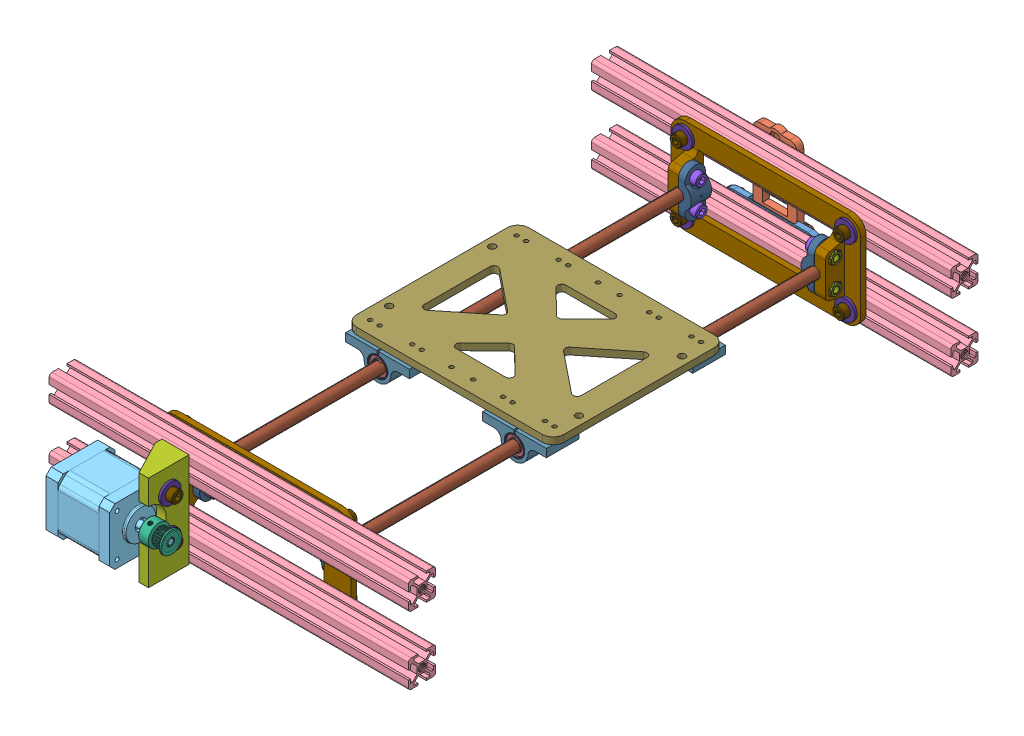
SolidWorks assembly Assembly_Y-Axis, configuration Default. Lengths in mm.
Overall size (265 71.5 493.71).
75 component instances, 20 part files, 169 mates.
Components (placement in the parent):
- Y Idler Mount-1: Y Idler Mount [Default] at (-290.2209 60.0349 127.2239) size (73.51 20 15)
- Y Idler Tensioner-2: Y Idler Tensioner [Default] at (-237.7209 60.0349 124.7239) x (-1 0 0) z (0 -1 0) size (32.5 17.63 71.5)
- instrument ball bearing_ai-1: instrument ball bearing_ai [AFBMA 12.2 - 0.3750 - 0.8750 - 0.2812 - 10,SI,NC,10] at (-250.0422 94.9749 116.2239) size (7.14 22.23 22.23)
- instrument ball bearing_ai-2: instrument ball bearing_ai [AFBMA 12.2 - 0.3750 - 0.8750 - 0.2812 - 10,SI,NC,10] at (-257.8997 94.9749 116.2239) size (7.14 22.23 22.23)
- 8020 26.5cm-1: 8020 26.5cm [Default] at (-366.7209 70.0349 137.2239) x (0 0 -1) z (1 0 0) size (20 20 265)
- 8020 26.5cm-2: 8020 26.5cm [Default] at (-366.7209 120.0349 137.2239) x (0 0 -1) z (1 0 0) size (20 20 265)
- 8020 26.5cm-3: 8020 26.5cm [Default] at (-101.7209 70.0349 537.2239) x (0 0 1) z (-1 0 0) size (20 20 265)
- 8020 26.5cm-4: 8020 26.5cm [Default] at (-101.7209 120.0349 537.2239) x (0 0 1) z (-1 0 0) size (20 20 265)
- Motor - NEMA17-1: Motor - NEMA17 [Default] at (-270.4709 98.1349 577.8256) x (0 -1 0) z (1 0 0) size (42 42 71)
- Motor Rotor Belt holder-1: Motor Rotor Belt holder [Default] at (-253.8985 99.0896 575.515) x (-1 0 0) z (0 -0.924225 -0.381849) size (16.47 16 16)
- YMotorMount-1: YMotorMount [Default] at (-263.4709 60.0349 547.2239) x (0 1 0) z (1 0 0) size (70 30 20)
- socket head cap screw_am-4: socket head cap screw_am [B18.3.1M - 5 x 0.8 x 10 Hex SHCS -- 10CHX] at (-276.4709 120.0349 557.2239) x (0 0 -1) z (1 0 0) size (15 8.5 8.5)
- socket head cap screw_am-5: socket head cap screw_am [B18.3.1M - 5 x 0.8 x 10 Hex SHCS -- 10CHX] at (-276.4709 70.0349 557.2239) x (0 0 -1) z (1 0 0) size (15 8.5 8.5)
- hollow_bracket-2: hollow_bracket [Default] at (-304.2209 60.0349 147.2239) size (140 70 18)
- hollow_bracket-3: hollow_bracket [Default] at (-164.2209 60.0349 527.2239) x (-1 0 0) z (0 0 -1) size (140 70 18)
- 7.5mm speed bump-1: 7.5mm speed bump [Default] at (-184.2209 95.1599 516.2239) x (0 1 0) z (0 0 1) size (35 10 15)
- 7.5mm speed bump-2: 7.5mm speed bump [Default] at (-284.2209 95.1599 516.2239) x (0 -1 0) z (0 0 1) size (35 10 15)
- 7.5mm speed bump-3: 7.5mm speed bump [Default] at (-284.2209 95.1599 158.2239) x (0 -1 0) z (0 0 1) size (35 10 15)
- 7.5mm speed bump-4: 7.5mm speed bump [Default] at (-184.2209 95.1599 158.2239) x (0 1 0) z (0 0 1) size (35 10 15)
- 38cm Aluminum rod-1: 38cm Aluminum rod [Default] at (-184.2209 95.0349 147.2239) size (7.94 7.94 380)
- 38cm Aluminum rod-2: 38cm Aluminum rod [Default] at (-284.2209 95.0349 147.2239) size (7.94 7.94 380)
- X Sub Plate-1: X Sub Plate [Default] at (-158.2023 110.0577 257.0427) x (-1 0 0) z (0 0 1) size (153 5 127)
- LM8UU-1: LM8UU [Default] at (-285.1836 95.0349 374.5427) x (0 0 -1) z (0.555945 0.831219 0) size (24 15 15)
- LM8UU_Bearing_Holder_(full_Circle_Speedbump)-1: LM8UU_Bearing_Holder_(full_Circle_Speedbump) [Default] at (-308.7023 105.0577 386.5427) x (1 0 0) z (0 1 0) size (47 24 20.05)
- LM8UU-2: LM8UU [Default] at (-285.1836 95.0349 266.5427) x (0 0 -1) z (0.555945 0.831219 0) size (24 15 15)
- LM8UU-3: LM8UU [Default] at (-184.2209 95.0349 266.5427) x (0 0 -1) z (0.555945 0.831219 0) size (24 15 15)
- LM8UU_Bearing_Holder_(full_Circle_Speedbump)-2: LM8UU_Bearing_Holder_(full_Circle_Speedbump) [Default] at (-207.7395 105.0577 278.5427) x (1 0 0) z (0 1 0) size (47 24 20.05)
- LM8UU_Bearing_Holder_(full_Circle_Speedbump)-3: LM8UU_Bearing_Holder_(full_Circle_Speedbump) [Default] at (-308.7023 105.0577 278.5427) x (1 0 0) z (0 1 0) size (47 24 20.05)
- LM8UU-4: LM8UU [Default] at (-184.2209 95.0349 374.5427) x (0 0 -1) z (0.555945 0.831219 0) size (24 15 15)
- LM8UU_Bearing_Holder_(full_Circle_Speedbump)-4: LM8UU_Bearing_Holder_(full_Circle_Speedbump) [Default] at (-207.7395 105.0577 386.5427) x (1 0 0) z (0 1 0) size (47 24 20.05)
- socket head cap screw_am-24: socket head cap screw_am [B18.3.1M - 5 x 0.8 x 10 Hex SHCS -- 10CHX] at (-229.2209 66.0349 118.2239) x (-1 0 0) z (0 0.924225 0.381849) size (15 8.5 8.5)
- socket set screw oval point_am-1: socket set screw oval point_am [B18.3.6M - M3 x 0.5 x 5 Hex Socket Oval Pt. SS --C] at (-258.5439 105.616 580.9059) x (-0.021896 -0.941534 -0.336206) z (-0.516982 0.298498 -0.802264) size (5 3 3)
- socket head cap screw_am-26: socket head cap screw_am [B18.3.1M - 5 x 0.8 x 10 Hex SHCS -- 10CHX] at (-274.2209 105.1599 516.2239) x (-1 0 0) z (0 0.924225 0.381849) size (15 8.5 8.5)
- socket head cap screw_am-27: socket head cap screw_am [B18.3.1M - 5 x 0.8 x 10 Hex SHCS -- 10CHX] at (-194.2209 105.1599 516.2239) size (15 8.5 8.5)
- socket head cap screw_am-28: socket head cap screw_am [B18.3.1M - 5 x 0.8 x 10 Hex SHCS -- 10CHX] at (-194.2209 85.1599 516.2239) size (15 8.5 8.5)
- socket head cap screw_am-29: socket head cap screw_am [B18.3.1M - 5 x 0.8 x 10 Hex SHCS -- 10CHX] at (-274.2209 85.1599 516.2239) x (-1 0 0) z (0 0.924225 0.381849) size (15 8.5 8.5)
- socket head cap screw_am-30: socket head cap screw_am [B18.3.1M - 5 x 0.8 x 10 Hex SHCS -- 10CHX] at (-274.2209 85.1599 158.2239) x (-1 0 0) z (0 0.924225 0.381849) size (15 8.5 8.5)
- socket head cap screw_am-31: socket head cap screw_am [B18.3.1M - 5 x 0.8 x 10 Hex SHCS -- 10CHX] at (-274.2209 105.1599 158.2239) x (-1 0 0) z (0 0.924225 0.381849) size (15 8.5 8.5)
- socket head cap screw_am-32: socket head cap screw_am [B18.3.1M - 5 x 0.8 x 10 Hex SHCS -- 10CHX] at (-194.2209 105.1599 158.2239) size (15 8.5 8.5)
- socket head cap screw_am-33: socket head cap screw_am [B18.3.1M - 5 x 0.8 x 10 Hex SHCS -- 10CHX] at (-194.2209 85.1599 158.2239) size (15 8.5 8.5)
- socket head cap screw_am-34: socket head cap screw_am [B18.3.1M - 5 x 0.8 x 10 Hex SHCS -- 10CHX] at (-280.2209 66.0349 118.2239) size (15 8.5 8.5)
- AM-M5-C-2: AM-M5-C [AM-M5-C] at (-174.9209 84.9099 516.2239) x (0 0 -1) z (1 0 0) size (8 9.81 5.3)
- AM-M5-C-3: AM-M5-C [AM-M5-C] at (-174.9209 105.1599 516.2239) x (0 0 -1) z (1 0 0) size (8 9.81 5.3)
- AM-M5-C-4: AM-M5-C [AM-M5-C] at (-174.9209 105.1599 158.2239) x (0 0 -1) z (1 0 0) size (8 9.81 5.3)
- AM-M5-C-5: AM-M5-C [AM-M5-C] at (-174.9209 84.9099 158.2239) x (0 0 -1) z (1 0 0) size (8 9.81 5.3)
- AM-M5-C-6: AM-M5-C [AM-M5-C] at (-293.5209 105.1599 158.2239) x (0 0 1) z (-1 0 0) size (8 9.81 5.3)
- AM-M5-C-7: AM-M5-C [AM-M5-C] at (-293.5209 84.9099 158.2239) x (0 0 1) z (-1 0 0) size (8 9.81 5.3)
- AM-M5-C-8: AM-M5-C [AM-M5-C] at (-293.5209 105.1599 516.2239) x (0 0 1) z (-1 0 0) size (8 9.81 5.3)
- AM-M5-C-9: AM-M5-C [AM-M5-C] at (-293.5209 84.9099 516.2239) x (0 0 1) z (-1 0 0) size (8 9.81 5.3)
- B18.22M - Plain washer, 5 mm, regular-1: B18.22M - Plain washer, 5 mm, regular [B18.22M - Plain washer, 5 mm, regular] at (-263.4709 113.6349 562.3256) x (-1 0 0) z (0 0.924225 0.381849) size (1.75 15 15)
- B18.22M - Plain washer, 5 mm, regular-2: B18.22M - Plain washer, 5 mm, regular [B18.22M - Plain washer, 5 mm, regular] at (-263.4709 84.0349 562.3256) x (-1 0 0) z (0 0.924225 0.381849) size (1.75 15 15)
- B18.22M - Plain washer, 5 mm, regular-3: B18.22M - Plain washer, 5 mm, regular [B18.22M - Plain washer, 5 mm, regular] at (-174.2209 120.0349 523.2239) x (0 0 1) z (-1 0 0) size (1.75 15 15)
- B18.22M - Plain washer, 5 mm, regular-4: B18.22M - Plain washer, 5 mm, regular [B18.22M - Plain washer, 5 mm, regular] at (-294.2209 120.0349 523.2239) x (0 0 1) z (-1 0 0) size (1.75 15 15)
- B18.22M - Plain washer, 5 mm, regular-5: B18.22M - Plain washer, 5 mm, regular [B18.22M - Plain washer, 5 mm, regular] at (-294.2209 70.0349 523.2239) x (0 0 1) z (-1 0 0) size (1.75 15 15)
- B18.22M - Plain washer, 5 mm, regular-6: B18.22M - Plain washer, 5 mm, regular [B18.22M - Plain washer, 5 mm, regular] at (-174.2209 70.0349 523.2239) x (0 0 1) z (-1 0 0) size (1.75 15 15)
- B18.22M - Plain washer, 5 mm, regular-7: B18.22M - Plain washer, 5 mm, regular [B18.22M - Plain washer, 5 mm, regular] at (-285.4749 70.0349 123.2239) x (0 0 1) z (-1 0 0) size (1.75 15 15)
- B18.22M - Plain washer, 5 mm, regular-8: B18.22M - Plain washer, 5 mm, regular [B18.22M - Plain washer, 5 mm, regular] at (-223.9669 70.0349 123.2239) x (0 0 1) z (-1 0 0) size (1.75 15 15)
- B18.22M - Plain washer, 5 mm, regular-9: B18.22M - Plain washer, 5 mm, regular [B18.22M - Plain washer, 5 mm, regular] at (-294.2209 120.0349 151.2239) x (0 0 -1) z (1 0 0) size (1.75 15 15)
- B18.22M - Plain washer, 5 mm, regular-10: B18.22M - Plain washer, 5 mm, regular [B18.22M - Plain washer, 5 mm, regular] at (-174.2209 120.0349 151.2239) x (0 0 -1) z (1 0 0) size (1.75 15 15)
- B18.22M - Plain washer, 5 mm, regular-11: B18.22M - Plain washer, 5 mm, regular [B18.22M - Plain washer, 5 mm, regular] at (-294.2209 70.0349 151.2239) x (0 0 -1) z (1 0 0) size (1.75 15 15)
- B18.22M - Plain washer, 5 mm, regular-12: B18.22M - Plain washer, 5 mm, regular [B18.22M - Plain washer, 5 mm, regular] at (-174.2209 70.0349 151.2239) x (0 0 -1) z (1 0 0) size (1.75 15 15)
- B18.3.1M - 5 x 0.8 x 10 Hex SHCS -- 10CHX-7: B18.3.1M - 5 x 0.8 x 10 Hex SHCS -- 10CHX [B18.3.1M - 5 x 0.8 x 10 Hex SHCS -- 10CHX] at (-294.2209 120.0349 157.9739) x (0 0 -1) z (1 0 0) size (15 8.5 8.5)
- B18.3.1M - 5 x 0.8 x 10 Hex SHCS -- 10CHX-8: B18.3.1M - 5 x 0.8 x 10 Hex SHCS -- 10CHX [B18.3.1M - 5 x 0.8 x 10 Hex SHCS -- 10CHX] at (-294.2209 70.0349 157.9739) x (0 0 -1) z (1 0 0) size (15 8.5 8.5)
- B18.3.1M - 5 x 0.8 x 10 Hex SHCS -- 10CHX-9: B18.3.1M - 5 x 0.8 x 10 Hex SHCS -- 10CHX [B18.3.1M - 5 x 0.8 x 10 Hex SHCS -- 10CHX] at (-174.2209 120.0349 157.9739) x (0 0 -1) z (1 0 0) size (15 8.5 8.5)
- B18.3.1M - 5 x 0.8 x 10 Hex SHCS -- 10CHX-10: B18.3.1M - 5 x 0.8 x 10 Hex SHCS -- 10CHX [B18.3.1M - 5 x 0.8 x 10 Hex SHCS -- 10CHX] at (-174.2209 70.0349 157.9739) x (0 0 -1) z (1 0 0) size (15 8.5 8.5)
- B18.3.1M - 5 x 0.8 x 10 Hex SHCS -- 10CHX-11: B18.3.1M - 5 x 0.8 x 10 Hex SHCS -- 10CHX [B18.3.1M - 5 x 0.8 x 10 Hex SHCS -- 10CHX] at (-223.9669 70.0349 116.4739) x (0 0 1) z (-1 0 0) size (15 8.5 8.5)
- B18.3.1M - 5 x 0.8 x 10 Hex SHCS -- 10CHX-12: B18.3.1M - 5 x 0.8 x 10 Hex SHCS -- 10CHX [B18.3.1M - 5 x 0.8 x 10 Hex SHCS -- 10CHX] at (-285.4749 70.0349 116.4739) x (0 0 1) z (-1 0 0) size (15 8.5 8.5)
- B18.3.1M - 5 x 0.8 x 10 Hex SHCS -- 10CHX-13: B18.3.1M - 5 x 0.8 x 10 Hex SHCS -- 10CHX [B18.3.1M - 5 x 0.8 x 10 Hex SHCS -- 10CHX] at (-174.2209 120.0349 516.4739) x (0 0 1) z (-1 0 0) size (15 8.5 8.5)
- B18.3.1M - 5 x 0.8 x 10 Hex SHCS -- 10CHX-14: B18.3.1M - 5 x 0.8 x 10 Hex SHCS -- 10CHX [B18.3.1M - 5 x 0.8 x 10 Hex SHCS -- 10CHX] at (-174.2209 70.0349 516.4739) x (0 0 1) z (-1 0 0) size (15 8.5 8.5)
- B18.3.1M - 5 x 0.8 x 10 Hex SHCS -- 10CHX-15: B18.3.1M - 5 x 0.8 x 10 Hex SHCS -- 10CHX [B18.3.1M - 5 x 0.8 x 10 Hex SHCS -- 10CHX] at (-294.2209 120.0349 516.4739) x (0 0 1) z (-1 0 0) size (15 8.5 8.5)
- B18.3.1M - 5 x 0.8 x 10 Hex SHCS -- 10CHX-16: B18.3.1M - 5 x 0.8 x 10 Hex SHCS -- 10CHX [B18.3.1M - 5 x 0.8 x 10 Hex SHCS -- 10CHX] at (-294.2209 70.0349 516.4739) x (0 0 1) z (-1 0 0) size (15 8.5 8.5)
- B18.3.1M - 5 x 0.8 x 10 Hex SHCS -- 10CHX-17: B18.3.1M - 5 x 0.8 x 10 Hex SHCS -- 10CHX [B18.3.1M - 5 x 0.8 x 10 Hex SHCS -- 10CHX] at (-256.7209 113.6349 562.3256) x (-1 0 0) z (0 0.924225 0.381849) size (15 8.5 8.5)
- B18.3.1M - 5 x 0.8 x 10 Hex SHCS -- 10CHX-18: B18.3.1M - 5 x 0.8 x 10 Hex SHCS -- 10CHX [B18.3.1M - 5 x 0.8 x 10 Hex SHCS -- 10CHX] at (-256.7209 84.0349 562.3256) x (-1 0 0) z (0 0.924225 0.381849) size (15 8.5 8.5)
- B18.2.4.5M - Hex jam nut,  M8 x 1.25 --D-C-2: B18.2.4.5M - Hex jam nut,  M8 x 1.25 --D-C [B18.2.4.5M - Hex jam nut,  M8 x 1.25 --D-C] at (-271.2209 94.9749 116.2239) x (0 0 1) z (-1 0 0) size (13 15.01 4)
- B18.3.1M - 8 x 1.25 x 30 Hex SHCS -- 30CHX-1: B18.3.1M - 8 x 1.25 x 30 Hex SHCS -- 30CHX [B18.3.1M - 8 x 1.25 x 30 Hex SHCS -- 30CHX] at (-232.7209 94.9749 116.2239) x (-1 0 0) z (0 0.924225 0.381849) size (38 13 13)
Mates (geometry in assembly coordinates):
- Coincident3: coincident aligned: plane of Y Idler Mount-1 through (-290.2209 60.0349 123.2239) normal (0 -1 0); plane of Y Idler Tensioner-2 through (-237.7209 60.0349 106.4439) normal (0 -1 0)
- Concentric1: concentric aligned: cylinder of Y Idler Tensioner-2 through (-270.2209 94.9749 116.2239) axis (1 0 0) radius 3.75; circle of instrument ball bearing_ai-1
- Concentric2: concentric aligned: circle of Y Idler Tensioner-2; circle of instrument ball bearing_ai-2
- Distance1: distance = 1.75 mm anti-aligned: plane of instrument ball bearing_ai-2 through (-261.4709 101.6424 116.2239) normal (-1 0 0); plane of Y Idler Tensioner-2 through (-263.2209 80.0349 106.4439) normal (1 0 0)
- Distance2: distance = 1.75 mm anti-aligned: plane of instrument ball bearing_ai-1 through (-246.4709 105.681 116.2239) normal (1 0 0); plane of Y Idler Tensioner-2 through (-244.7209 80.0349 106.4439) normal (-1 0 0)
- Coincident6: coincident anti-aligned: plane of Y Idler Mount-1 through (-290.2209 60.0349 127.2239) normal (0 0 1); plane of 8020 26.5cm-1 through (-101.7209 70.0349 127.2239) normal (0 0 -1)
- Coincident7: coincident aligned: plane of Y Idler Mount-1 through (-290.2209 60.0349 123.2239) normal (0 -1 0); plane of 8020 26.5cm-1 through (-101.7209 60.0349 137.2239) normal (0 -1 0)
- Distance3: distance = 132.5 mm aligned: plane of Y Idler Mount-1 through (-234.2209 66.0349 118.2239) normal (1 0 0); plane of 8020 26.5cm-1 through (-101.7209 70.0349 137.2239) normal (1 0 0)
- Coincident9: coincident aligned: plane of 8020 26.5cm-1 through (-366.7209 70.0349 137.2239) normal (-1 0 0); plane of 8020 26.5cm-2 through (-366.7209 120.0349 137.2239) normal (-1 0 0)
- Coincident21: coincident aligned: plane of 8020 26.5cm-3 through (-366.7209 60.0349 537.2239) normal (0 -1 0); plane of YMotorMount-1 through (-270.4709 60.0349 547.2239) normal (0 -1 0)
- Coincident33: coincident aligned: plane of 8020 26.5cm-4 through (-366.7209 130.0349 537.2239) normal (0 1 0); plane of YMotorMount-1 through (-270.4709 130.0349 547.2239) normal (0 1 0)
- Coincident34: coincident aligned: plane of 8020 26.5cm-3 through (-366.7209 70.0349 537.2239) normal (-1 0 0); plane of 8020 26.5cm-4 through (-366.7209 120.0349 537.2239) normal (-1 0 0)
- Coincident35: coincident aligned: plane of 8020 26.5cm-2 through (-101.7209 130.0349 137.2239) normal (0 1 0); plane of 8020 26.5cm-4 through (-366.7209 130.0349 537.2239) normal (0 1 0)
- Concentric4: concentric aligned: circle of Motor - NEMA17-1; circle of YMotorMount-1
- Parallel4: parallel aligned: plane of Motor - NEMA17-1 through (-278.4709 80.9512 598.8256) normal (0 0 1); plane of YMotorMount-1 through (-270.4709 60.0349 577.2239) normal (0 0 1)
- Coincident37: coincident anti-aligned: plane of Motor - NEMA17-1 through (-270.4709 98.1349 577.8256) normal (1 0 0); plane of YMotorMount-1 through (-270.4709 98.8349 577.2239) normal (-1 0 0)
- Coincident38: coincident aligned: plane of Motor - NEMA17-1 through (-246.4709 98.1349 577.8256) normal (1 0 0); plane of Motor Rotor Belt holder-1 through (-246.4709 99.0896 575.515) normal (1 0 0)
- Coincident39: coincident anti-aligned: cylinder of Motor - NEMA17-1 through (-246.4709 98.1349 577.8256) axis (-1 0 0) radius 2.5; circle of Motor Rotor Belt holder-1
- Coincident40: coincident aligned: plane of instrument ball bearing_ai-1 through (-246.4709 105.681 116.2239) normal (1 0 0); plane of Motor Rotor Belt holder-1 through (-246.4709 99.0896 575.515) normal (1 0 0)
- Concentric81: concentric anti-aligned: cylinder of YMotorMount-1 through (-276.4709 120.0349 552.2239) axis (0 0 -1) radius 3; cylinder of socket head cap screw_am-4 through (-276.4709 120.0349 588.9739) axis (0 0 1) radius 4.25
- Coincident441: coincident anti-aligned: plane of YMotorMount-1 through (-263.4709 60.0349 552.2239) normal (0 0 1); plane of socket head cap screw_am-4 through (-276.4709 124.2849 552.2239) normal (0 0 -1)
- Concentric91: concentric anti-aligned: cylinder of YMotorMount-1 through (-276.4709 70.0349 552.2239) axis (0 0 -1) radius 3; cylinder of socket head cap screw_am-5 through (-276.4709 70.0349 588.9739) axis (0 0 1) radius 4.25
- Coincident451: coincident anti-aligned: plane of YMotorMount-1 through (-263.4709 60.0349 552.2239) normal (0 0 1); plane of socket head cap screw_am-5 through (-276.4709 74.2849 552.2239) normal (0 0 -1)
- Coincident465: coincident aligned: plane of 8020 26.5cm-1 through (-101.7209 70.0349 127.2239) normal (0 0 -1); plane of 8020 26.5cm-2 through (-101.7209 120.0349 127.2239) normal (0 0 -1)
- Coincident466: coincident anti-aligned: plane of 8020 26.5cm-2 through (-101.7209 120.0349 147.2239) normal (0 0 1); plane of hollow_bracket-2 through (-304.2209 60.0349 147.2239) normal (0 0 -1)
- Coincident467: coincident aligned: plane of 8020 26.5cm-2 through (-101.7209 130.0349 137.2239) normal (0 1 0); plane of hollow_bracket-2 through (-304.2209 130.0349 151.2239) normal (0 1 0)
- Distance4: distance = 62.5 mm aligned: plane of 8020 26.5cm-2 through (-366.7209 120.0349 137.2239) normal (-1 0 0); plane of hollow_bracket-2 through (-304.2209 60.0349 151.2239) normal (-1 0 0)
- Coincident469: coincident anti-aligned: plane of 8020 26.5cm-4 through (-366.7209 120.0349 527.2239) normal (0 0 -1); plane of hollow_bracket-3 through (-164.2209 60.0349 527.2239) normal (0 0 1)
- Coincident470: coincident aligned: plane of 8020 26.5cm-4 through (-366.7209 130.0349 537.2239) normal (0 1 0); plane of hollow_bracket-3 through (-164.2209 130.0349 523.2239) normal (0 1 0)
- Coincident471: coincident aligned: plane of hollow_bracket-2 through (-164.2209 60.0349 151.2239) normal (1 0 0); plane of hollow_bracket-3 through (-164.2209 60.0349 523.2239) normal (1 0 0)
- Coincident472: coincident aligned: circle of hollow_bracket-3; circle of 7.5mm speed bump-1
- Parallel6: parallel aligned: plane of hollow_bracket-3 through (-164.2209 60.0349 509.2239) normal (0 0 -1); plane of 7.5mm speed bump-1 through (-193.7209 95.1599 508.7239) normal (0 0 -1)
- Coincident474: coincident aligned: circle of hollow_bracket-3; circle of 7.5mm speed bump-2
- Parallel7: parallel aligned: plane of hollow_bracket-3 through (-164.2209 60.0349 509.2239) normal (0 0 -1); plane of 7.5mm speed bump-2 through (-274.7209 95.1599 508.7239) normal (0 0 -1)
- Coincident477: coincident aligned: circle of hollow_bracket-2; circle of 7.5mm speed bump-4
- Parallel8: parallel aligned: plane of 7.5mm speed bump-4 through (-193.7209 95.1599 165.7239) normal (0 0 1); plane of hollow_bracket-2 through (-304.2209 60.0349 165.2239) normal (0 0 1)
- Coincident482: coincident aligned: circle of hollow_bracket-2; circle of 7.5mm speed bump-3
- Parallel9: parallel aligned: plane of hollow_bracket-2 through (-304.2209 60.0349 165.2239) normal (0 0 1); plane of 7.5mm speed bump-3 through (-274.7209 95.1599 165.7239) normal (0 0 1)
- Concentric102: concentric anti-aligned: circle of hollow_bracket-2; cylinder of 38cm Aluminum rod-1 through (-184.2209 95.0349 527.2239) axis (0 0 -1) radius 3.9688
- Coincident484: coincident aligned: plane of hollow_bracket-2 through (-304.2209 60.0349 147.2239) normal (0 0 -1); plane of 38cm Aluminum rod-1 through (-184.2209 95.0349 147.2239) normal (0 0 -1)
- Concentric103: concentric anti-aligned: cylinder of hollow_bracket-2 through (-284.2209 95.0349 147.2239) axis (0 0 1) radius 4.125; cylinder of 38cm Aluminum rod-2 through (-284.2209 95.0349 527.2239) axis (0 0 -1) radius 3.9688
- Coincident485: coincident aligned: plane of hollow_bracket-2 through (-304.2209 60.0349 147.2239) normal (0 0 -1); plane of 38cm Aluminum rod-2 through (-284.2209 95.0349 147.2239) normal (0 0 -1)
- Concentric104: concentric anti-aligned: cylinder of LM8UU-1 through (-285.1836 95.0349 420.2322) axis (0 0 1) radius 7.5; cylinder of LM8UU_Bearing_Holder_(full_Circle_Speedbump)-1 through (-285.1836 95.0349 386.5427) axis (0 0 -1) radius 7.55
- Coincident486: coincident aligned: circle of LM8UU-1; plane of LM8UU_Bearing_Holder_(full_Circle_Speedbump)-1 through (-270.2023 93.9899 386.5427) normal (0 0 1)
- Concentric105: concentric anti-aligned: cylinder of LM8UU-3 through (-184.2209 95.0349 312.2322) axis (0 0 1) radius 7.5; cylinder of LM8UU_Bearing_Holder_(full_Circle_Speedbump)-2 through (-184.2209 95.0349 278.5427) axis (0 0 -1) radius 7.55
- Concentric106: concentric anti-aligned: cylinder of LM8UU-4 through (-184.2209 95.0349 420.2322) axis (0 0 1) radius 7.5; cylinder of LM8UU_Bearing_Holder_(full_Circle_Speedbump)-4 through (-184.2209 95.0349 386.5427) axis (0 0 -1) radius 7.55
- Concentric107: concentric anti-aligned: cylinder of LM8UU-2 through (-285.1836 95.0349 312.2322) axis (0 0 1) radius 7.5; cylinder of LM8UU_Bearing_Holder_(full_Circle_Speedbump)-3 through (-285.1836 95.0349 278.5427) axis (0 0 -1) radius 7.55
- Coincident487: coincident aligned: plane of LM8UU-4 through (-184.2209 95.0349 362.5427) normal (0 0 -1); plane of LM8UU_Bearing_Holder_(full_Circle_Speedbump)-4 through (-169.2395 93.9899 362.5427) normal (0 0 -1)
- Coincident488: coincident aligned: circle of LM8UU-3; plane of LM8UU_Bearing_Holder_(full_Circle_Speedbump)-2 through (-169.2395 93.9899 278.5427) normal (0 0 1)
- Coincident489: coincident aligned: plane of LM8UU-2 through (-285.1836 95.0349 278.5427) normal (0 0 1); plane of LM8UU_Bearing_Holder_(full_Circle_Speedbump)-3 through (-270.2023 93.9899 278.5427) normal (0 0 1)
- Coincident494: coincident anti-aligned: plane of X Sub Plate-1 through (-158.2023 105.0577 257.0427) normal (0 -1 0); plane of LM8UU_Bearing_Holder_(full_Circle_Speedbump)-2 through (-207.7395 105.0577 278.5427) normal (0 1 0)
- Parallel11: parallel anti-aligned: plane of X Sub Plate-1 through (-158.2023 105.0577 257.0427) normal (0 0 -1); plane of LM8UU_Bearing_Holder_(full_Circle_Speedbump)-2 through (-169.2395 93.9899 278.5427) normal (0 0 1)
- Concentric118: concentric aligned: circle of X Sub Plate-1; circle of LM8UU_Bearing_Holder_(full_Circle_Speedbump)-2
- Coincident496: coincident anti-aligned: plane of X Sub Plate-1 through (-158.2023 105.0577 257.0427) normal (0 -1 0); plane of LM8UU_Bearing_Holder_(full_Circle_Speedbump)-4 through (-207.7395 105.0577 386.5427) normal (0 1 0)
- Concentric119: concentric anti-aligned: circle of X Sub Plate-1; circle of LM8UU_Bearing_Holder_(full_Circle_Speedbump)-4
- Coincident497: coincident anti-aligned: plane of X Sub Plate-1 through (-158.2023 105.0577 257.0427) normal (0 -1 0); plane of LM8UU_Bearing_Holder_(full_Circle_Speedbump)-3 through (-308.7023 105.0577 278.5427) normal (0 1 0)
- Concentric120: concentric anti-aligned: circle of X Sub Plate-1; cylinder of LM8UU_Bearing_Holder_(full_Circle_Speedbump)-3 through (-302.7023 99.0577 266.5427) axis (0 -1 0) radius 2.25
- Coincident498: coincident anti-aligned: plane of X Sub Plate-1 through (-158.2023 105.0577 257.0427) normal (0 -1 0); plane of LM8UU_Bearing_Holder_(full_Circle_Speedbump)-1 through (-308.7023 105.0577 386.5427) normal (0 1 0)
- Concentric122: concentric aligned: circle of X Sub Plate-1; circle of LM8UU_Bearing_Holder_(full_Circle_Speedbump)-1
- Parallel12: parallel aligned: plane of X Sub Plate-1 through (-158.2023 105.0577 384.0427) normal (0 0 1); plane of LM8UU_Bearing_Holder_(full_Circle_Speedbump)-4 through (-169.2395 93.9899 386.5427) normal (0 0 1)
- Parallel13: parallel aligned: plane of X Sub Plate-1 through (-158.2023 105.0577 384.0427) normal (0 0 1); plane of LM8UU_Bearing_Holder_(full_Circle_Speedbump)-1 through (-270.2023 93.9899 386.5427) normal (0 0 1)
- Parallel14: parallel aligned: plane of X Sub Plate-1 through (-158.2023 105.0577 257.0427) normal (0 0 -1); plane of LM8UU_Bearing_Holder_(full_Circle_Speedbump)-2 through (-169.2395 93.9899 254.5427) normal (0 0 -1)
- Parallel15: parallel aligned: plane of X Sub Plate-1 through (-158.2023 105.0577 257.0427) normal (0 0 -1); plane of LM8UU_Bearing_Holder_(full_Circle_Speedbump)-3 through (-270.2023 93.9899 254.5427) normal (0 0 -1)
- Coincident503: coincident aligned: plane of 8020 26.5cm-3 through (-366.7209 60.0349 537.2239) normal (0 -1 0); plane of hollow_bracket-3 through (-164.2209 60.0349 523.2239) normal (0 -1 0)
- Coincident505: coincident aligned: plane of 8020 26.5cm-1 through (-101.7209 70.0349 137.2239) normal (1 0 0); plane of 8020 26.5cm-3 through (-101.7209 70.0349 537.2239) normal (1 0 0)
- Coincident506: coincident aligned: plane of 8020 26.5cm-3 through (-366.7209 70.0349 547.2239) normal (0 0 1); plane of 8020 26.5cm-4 through (-366.7209 120.0349 547.2239) normal (0 0 1)
- Coincident507: coincident aligned: plane of hollow_bracket-3 through (-164.2209 60.0349 527.2239) normal (0 0 1); plane of 38cm Aluminum rod-1 through (-184.2209 95.0349 527.2239) normal (0 0 1)
- Coincident508: coincident aligned: plane of hollow_bracket-3 through (-164.2209 60.0349 527.2239) normal (0 0 1); circle of 38cm Aluminum rod-2
- Coincident509: coincident aligned: plane of hollow_bracket-2 through (-304.2209 60.0349 147.2239) normal (0 0 -1); plane of 38cm Aluminum rod-2 through (-284.2209 95.0349 147.2239) normal (0 0 -1)
- Coincident510: coincident aligned: plane of hollow_bracket-2 through (-304.2209 60.0349 147.2239) normal (0 0 -1); plane of 38cm Aluminum rod-1 through (-184.2209 95.0349 147.2239) normal (0 0 -1)
- Coincident511: coincident aligned: plane of 8020 26.5cm-4 through (-366.7209 130.0349 537.2239) normal (0 1 0); plane of hollow_bracket-3 through (-164.2209 130.0349 523.2239) normal (0 1 0)
- Coincident512: coincident aligned: plane of Y Idler Mount-1 through (-290.2209 60.0349 123.2239) normal (0 -1 0); plane of 8020 26.5cm-1 through (-101.7209 60.0349 137.2239) normal (0 -1 0)
- Coincident513: coincident aligned: plane of 8020 26.5cm-1 through (-101.7209 80.0349 137.2239) normal (0 1 0); plane of 8020 26.5cm-3 through (-366.7209 80.0349 537.2239) normal (0 1 0)
- Coincident514: coincident anti-aligned: plane of 8020 26.5cm-4 through (-366.7209 120.0349 547.2239) normal (0 0 1); plane of YMotorMount-1 through (-270.4709 60.0349 547.2239) normal (0 0 -1)
- Coincident515: coincident aligned: plane of 8020 26.5cm-4 through (-366.7209 130.0349 537.2239) normal (0 1 0); plane of YMotorMount-1 through (-270.4709 130.0349 547.2239) normal (0 1 0)
- Parallel17: parallel anti-aligned: plane of Y Idler Tensioner-2 through (-244.7209 80.0349 106.4439) normal (-1 0 0); plane of Motor Rotor Belt holder-1 through (-246.4709 99.0896 575.515) normal (1 0 0)
- Parallel19: parallel aligned: plane of 8020 26.5cm-4 through (-366.7209 130.0349 537.2239) normal (0 1 0); plane of X Sub Plate-1 through (-158.2023 110.0577 257.0427) normal (0 1 0)
- Concentric130: concentric anti-aligned: cylinder of 38cm Aluminum rod-1 through (-184.2209 95.0349 527.2239) axis (0 0 -1) radius 3.9688; cylinder of LM8UU-4 through (-184.2209 95.0349 420.2322) axis (0 0 1) radius 4
- Concentric1472: concentric anti-aligned: cylinder of Y Idler Mount-1 through (-234.2209 66.0349 118.2239) axis (-1 0 0) radius 3; cylinder of Y Idler Tensioner-2 through (-270.2209 66.0349 118.2239) axis (1 0 0) radius 2.55
- Concentric14731: concentric anti-aligned: cylinder of Y Idler Mount-1 through (-234.2209 66.0349 118.2239) axis (-1 0 0) radius 3; cylinder of socket head cap screw_am-24 through (-197.4709 66.0349 118.2239) axis (1 0 0) radius 4.25
- Coincident53521: coincident anti-aligned: plane of Y Idler Mount-1 through (-234.2209 66.0349 118.2239) normal (1 0 0); plane of socket head cap screw_am-24 through (-234.2209 64.4121 122.1518) normal (-1 0 0)
- Tangent1: tangent: curve of Motor Rotor Belt holder-1; circle of socket set screw oval point_am-1
- Concentric148481: concentric anti-aligned: cylinder of 7.5mm speed bump-2 through (-279.2209 105.1599 516.2239) axis (-1 0 0) radius 2.75; cylinder of socket head cap screw_am-26 through (-242.4709 105.1599 516.2239) axis (1 0 0) radius 4.25
- Coincident536371: coincident anti-aligned: plane of 7.5mm speed bump-2 through (-279.2209 95.1599 516.2239) normal (1 0 0); plane of socket head cap screw_am-26 through (-279.2209 103.5371 520.1518) normal (-1 0 0)
- Concentric148491: concentric anti-aligned: cylinder of 7.5mm speed bump-1 through (-189.2209 105.1599 516.2239) axis (1 0 0) radius 2.75; cylinder of socket head cap screw_am-27 through (-225.9709 105.1599 516.2239) axis (-1 0 0) radius 4.25
- Coincident536381: coincident anti-aligned: plane of 7.5mm speed bump-1 through (-189.2209 95.1599 516.2239) normal (-1 0 0); plane of socket head cap screw_am-27 through (-189.2209 109.4099 516.2239) normal (1 0 0)
- Concentric148501: concentric anti-aligned: cylinder of 7.5mm speed bump-1 through (-189.2209 85.1599 516.2239) axis (1 0 0) radius 2.75; cylinder of socket head cap screw_am-28 through (-225.9709 85.1599 516.2239) axis (-1 0 0) radius 4.25
- Coincident536391: coincident anti-aligned: plane of 7.5mm speed bump-1 through (-189.2209 95.1599 516.2239) normal (-1 0 0); plane of socket head cap screw_am-28 through (-189.2209 89.4099 516.2239) normal (1 0 0)
- Concentric148511: concentric anti-aligned: cylinder of 7.5mm speed bump-2 through (-279.2209 85.1599 516.2239) axis (-1 0 0) radius 2.75; cylinder of socket head cap screw_am-29 through (-242.4709 85.1599 516.2239) axis (1 0 0) radius 4.25
- Coincident536401: coincident anti-aligned: plane of 7.5mm speed bump-2 through (-279.2209 95.1599 516.2239) normal (1 0 0); plane of socket head cap screw_am-29 through (-279.2209 83.5371 520.1518) normal (-1 0 0)
- Concentric148521: concentric anti-aligned: cylinder of 7.5mm speed bump-3 through (-279.2209 85.1599 158.2239) axis (-1 0 0) radius 2.75; cylinder of socket head cap screw_am-30 through (-242.4709 85.1599 158.2239) axis (1 0 0) radius 4.25
- Coincident536411: coincident anti-aligned: plane of 7.5mm speed bump-3 through (-279.2209 95.1599 158.2239) normal (1 0 0); plane of socket head cap screw_am-30 through (-279.2209 83.5371 162.1518) normal (-1 0 0)
- Concentric148531: concentric anti-aligned: cylinder of 7.5mm speed bump-3 through (-274.7209 105.1599 158.2239) axis (-1 0 0) radius 5.5; cylinder of socket head cap screw_am-31 through (-242.4709 105.1599 158.2239) axis (1 0 0) radius 4.25
- Coincident536421: coincident anti-aligned: plane of 7.5mm speed bump-3 through (-279.2209 95.1599 158.2239) normal (1 0 0); plane of socket head cap screw_am-31 through (-279.2209 103.5371 162.1518) normal (-1 0 0)
- Concentric148541: concentric anti-aligned: cylinder of 7.5mm speed bump-4 through (-189.2209 105.1599 158.2239) axis (1 0 0) radius 2.75; cylinder of socket head cap screw_am-32 through (-225.9709 105.1599 158.2239) axis (-1 0 0) radius 4.25
- Coincident536431: coincident anti-aligned: plane of 7.5mm speed bump-4 through (-189.2209 95.1599 158.2239) normal (-1 0 0); plane of socket head cap screw_am-32 through (-189.2209 109.4099 158.2239) normal (1 0 0)
- Concentric148551: concentric anti-aligned: cylinder of 7.5mm speed bump-4 through (-189.2209 85.1599 158.2239) axis (1 0 0) radius 2.75; cylinder of socket head cap screw_am-33 through (-225.9709 85.1599 158.2239) axis (-1 0 0) radius 4.25
- Coincident536441: coincident anti-aligned: plane of 7.5mm speed bump-4 through (-189.2209 95.1599 158.2239) normal (-1 0 0); plane of socket head cap screw_am-33 through (-189.2209 89.4099 158.2239) normal (1 0 0)
- Concentric148561: concentric anti-aligned: cylinder of Y Idler Mount-1 through (-275.2209 66.0349 118.2239) axis (1 0 0) radius 3; cylinder of socket head cap screw_am-34 through (-311.9709 66.0349 118.2239) axis (-1 0 0) radius 4.25
- Coincident536451: coincident anti-aligned: plane of Y Idler Mount-1 through (-275.2209 66.0349 118.2239) normal (-1 0 0); plane of socket head cap screw_am-34 through (-275.2209 70.2849 118.2239) normal (1 0 0)
- Coincident53646: coincident aligned: plane of hollow_bracket-3 through (-164.2209 60.0349 527.2239) normal (0 0 1); plane of 38cm Aluminum rod-1 through (-184.2209 95.0349 527.2239) normal (0 0 1)
- Concentric148571: concentric anti-aligned: cylinder of hollow_bracket-3 through (-180.2209 84.9099 516.2239) axis (-1 0 0) radius 2.75; cylinder of AM-M5-C-2 through (-199.9584 84.9099 516.2239) axis (1 0 0) radius 2.5
- Coincident536471: coincident anti-aligned: plane of hollow_bracket-3 through (-180.2209 60.0349 527.2239) normal (1 0 0); plane of AM-M5-C-2 through (-180.2209 84.9099 524.2239) normal (-1 0 0)
- Concentric148581: concentric anti-aligned: cylinder of hollow_bracket-3 through (-180.2209 105.1599 516.2239) axis (-1 0 0) radius 2.75; cylinder of AM-M5-C-3 through (-199.9584 105.1599 516.2239) axis (1 0 0) radius 2.5
- Coincident536481: coincident anti-aligned: plane of hollow_bracket-3 through (-180.2209 60.0349 527.2239) normal (1 0 0); plane of AM-M5-C-3 through (-180.2209 105.1599 524.2239) normal (-1 0 0)
- Concentric148591: concentric anti-aligned: cylinder of hollow_bracket-2 through (-180.2209 105.1599 158.2239) axis (-1 0 0) radius 2.75; cylinder of AM-M5-C-4 through (-199.9584 105.1599 158.2239) axis (1 0 0) radius 2.5
- Coincident536491: coincident anti-aligned: plane of hollow_bracket-2 through (-180.2209 60.0349 147.2239) normal (1 0 0); plane of AM-M5-C-4 through (-180.2209 105.1599 166.2239) normal (-1 0 0)
- Concentric148601: concentric anti-aligned: cylinder of hollow_bracket-2 through (-180.2209 84.9099 158.2239) axis (-1 0 0) radius 2.75; cylinder of AM-M5-C-5 through (-199.9584 84.9099 158.2239) axis (1 0 0) radius 2.5
- Coincident536501: coincident anti-aligned: plane of hollow_bracket-2 through (-180.2209 60.0349 147.2239) normal (1 0 0); plane of AM-M5-C-5 through (-180.2209 84.9099 166.2239) normal (-1 0 0)
- Concentric148611: concentric anti-aligned: cylinder of hollow_bracket-2 through (-288.2209 105.1599 158.2239) axis (1 0 0) radius 2.75; cylinder of AM-M5-C-6 through (-268.4834 105.1599 158.2239) axis (-1 0 0) radius 2.5
- Coincident536511: coincident anti-aligned: plane of hollow_bracket-2 through (-288.2209 60.0349 147.2239) normal (-1 0 0); plane of AM-M5-C-6 through (-288.2209 105.1599 150.2239) normal (1 0 0)
- Concentric148621: concentric anti-aligned: cylinder of hollow_bracket-2 through (-288.2209 84.9099 158.2239) axis (1 0 0) radius 2.75; cylinder of AM-M5-C-7 through (-268.4834 84.9099 158.2239) axis (-1 0 0) radius 2.5
- Coincident536521: coincident anti-aligned: plane of hollow_bracket-2 through (-288.2209 60.0349 147.2239) normal (-1 0 0); plane of AM-M5-C-7 through (-288.2209 84.9099 150.2239) normal (1 0 0)
- Concentric148631: concentric anti-aligned: cylinder of hollow_bracket-3 through (-288.2209 105.1599 516.2239) axis (1 0 0) radius 2.75; cylinder of AM-M5-C-8 through (-268.4834 105.1599 516.2239) axis (-1 0 0) radius 2.5
- Coincident536531: coincident anti-aligned: plane of hollow_bracket-3 through (-288.2209 60.0349 527.2239) normal (-1 0 0); plane of AM-M5-C-8 through (-288.2209 105.1599 508.2239) normal (1 0 0)
- Concentric148641: concentric anti-aligned: cylinder of hollow_bracket-3 through (-288.2209 84.9099 516.2239) axis (1 0 0) radius 2.75; cylinder of AM-M5-C-9 through (-268.4834 84.9099 516.2239) axis (-1 0 0) radius 2.5
- Coincident536541: coincident anti-aligned: plane of hollow_bracket-3 through (-288.2209 60.0349 527.2239) normal (-1 0 0); plane of AM-M5-C-9 through (-288.2209 84.9099 508.2239) normal (1 0 0)
- Concentric1486421: concentric aligned: cylinder of YMotorMount-1 through (-270.4709 113.6349 562.3256) axis (1 0 0) radius 2.5; cylinder of B18.22M - Plain washer, 5 mm, regular-1 through (-228.5459 113.6349 562.3256) axis (1 0 0) radius 2.89
- Coincident5365421: coincident anti-aligned: plane of YMotorMount-1 through (-263.4709 98.8349 577.2239) normal (1 0 0); plane of B18.22M - Plain washer, 5 mm, regular-1 through (-263.4709 112.5314 564.9966) normal (-1 0 0)
- Concentric1486431: concentric aligned: cylinder of YMotorMount-1 through (-270.4709 84.0349 562.3256) axis (1 0 0) radius 2.5; cylinder of B18.22M - Plain washer, 5 mm, regular-2 through (-228.5459 84.0349 562.3256) axis (1 0 0) radius 2.89
- Coincident5365431: coincident anti-aligned: plane of YMotorMount-1 through (-263.4709 98.8349 577.2239) normal (1 0 0); plane of B18.22M - Plain washer, 5 mm, regular-2 through (-263.4709 82.9314 564.9966) normal (-1 0 0)
- Concentric1486441: concentric anti-aligned: cylinder of hollow_bracket-3 through (-174.2209 120.0349 523.2239) axis (0 0 1) radius 2.75; cylinder of B18.22M - Plain washer, 5 mm, regular-3 through (-174.2209 120.0349 488.2989) axis (0 0 -1) radius 2.89
- Coincident5365441: coincident anti-aligned: plane of hollow_bracket-3 through (-164.2209 60.0349 523.2239) normal (0 0 -1); plane of B18.22M - Plain washer, 5 mm, regular-3 through (-174.2209 122.9249 523.2239) normal (0 0 1)
- Concentric1486451: concentric anti-aligned: cylinder of hollow_bracket-3 through (-294.2209 120.0349 523.2239) axis (0 0 1) radius 2.75; cylinder of B18.22M - Plain washer, 5 mm, regular-4 through (-294.2209 120.0349 488.2989) axis (0 0 -1) radius 2.89
- Coincident5365451: coincident anti-aligned: plane of hollow_bracket-3 through (-164.2209 60.0349 523.2239) normal (0 0 -1); plane of B18.22M - Plain washer, 5 mm, regular-4 through (-294.2209 122.9249 523.2239) normal (0 0 1)
- Concentric1486461: concentric anti-aligned: cylinder of hollow_bracket-3 through (-294.2209 70.0349 523.2239) axis (0 0 1) radius 2.75; cylinder of B18.22M - Plain washer, 5 mm, regular-5 through (-294.2209 70.0349 488.2989) axis (0 0 -1) radius 2.89
- Coincident5365461: coincident anti-aligned: plane of hollow_bracket-3 through (-164.2209 60.0349 523.2239) normal (0 0 -1); plane of B18.22M - Plain washer, 5 mm, regular-5 through (-294.2209 72.9249 523.2239) normal (0 0 1)
- Concentric1486471: concentric anti-aligned: cylinder of hollow_bracket-3 through (-174.2209 70.0349 523.2239) axis (0 0 1) radius 2.75; cylinder of B18.22M - Plain washer, 5 mm, regular-6 through (-174.2209 70.0349 488.2989) axis (0 0 -1) radius 2.89
- Coincident5365471: coincident anti-aligned: plane of hollow_bracket-3 through (-164.2209 60.0349 523.2239) normal (0 0 -1); plane of B18.22M - Plain washer, 5 mm, regular-6 through (-174.2209 72.9249 523.2239) normal (0 0 1)
- Concentric1486481: concentric anti-aligned: cylinder of Y Idler Mount-1 through (-285.4749 70.0349 123.2239) axis (0 0 1) radius 3; cylinder of B18.22M - Plain washer, 5 mm, regular-7 through (-285.4749 70.0349 88.2989) axis (0 0 -1) radius 2.89
- Coincident5365481: coincident anti-aligned: plane of Y Idler Mount-1 through (-290.2209 60.0349 123.2239) normal (0 0 -1); plane of B18.22M - Plain washer, 5 mm, regular-7 through (-285.4749 72.9249 123.2239) normal (0 0 1)
- Concentric1486491: concentric anti-aligned: cylinder of Y Idler Mount-1 through (-223.9669 70.0349 123.2239) axis (0 0 1) radius 3; cylinder of B18.22M - Plain washer, 5 mm, regular-8 through (-223.9669 70.0349 88.2989) axis (0 0 -1) radius 2.89
- Coincident5365491: coincident anti-aligned: plane of Y Idler Mount-1 through (-290.2209 60.0349 123.2239) normal (0 0 -1); plane of B18.22M - Plain washer, 5 mm, regular-8 through (-223.9669 72.9249 123.2239) normal (0 0 1)
- Concentric1486501: concentric anti-aligned: cylinder of hollow_bracket-2 through (-294.2209 120.0349 151.2239) axis (0 0 -1) radius 2.75; cylinder of B18.22M - Plain washer, 5 mm, regular-9 through (-294.2209 120.0349 186.1489) axis (0 0 1) radius 2.89
- Coincident5365501: coincident anti-aligned: plane of hollow_bracket-2 through (-304.2209 60.0349 151.2239) normal (0 0 1); plane of B18.22M - Plain washer, 5 mm, regular-9 through (-294.2209 122.9249 151.2239) normal (0 0 -1)
- Concentric1486511: concentric anti-aligned: cylinder of hollow_bracket-2 through (-174.2209 120.0349 151.2239) axis (0 0 -1) radius 2.75; cylinder of B18.22M - Plain washer, 5 mm, regular-10 through (-174.2209 120.0349 186.1489) axis (0 0 1) radius 2.89
- Coincident5365511: coincident anti-aligned: plane of hollow_bracket-2 through (-304.2209 60.0349 151.2239) normal (0 0 1); plane of B18.22M - Plain washer, 5 mm, regular-10 through (-174.2209 122.9249 151.2239) normal (0 0 -1)
- Concentric1486521: concentric anti-aligned: cylinder of hollow_bracket-2 through (-294.2209 70.0349 151.2239) axis (0 0 -1) radius 2.75; cylinder of B18.22M - Plain washer, 5 mm, regular-11 through (-294.2209 70.0349 186.1489) axis (0 0 1) radius 2.89
- Coincident5365521: coincident anti-aligned: plane of hollow_bracket-2 through (-304.2209 60.0349 151.2239) normal (0 0 1); plane of B18.22M - Plain washer, 5 mm, regular-11 through (-294.2209 72.9249 151.2239) normal (0 0 -1)
- Concentric1486531: concentric anti-aligned: cylinder of hollow_bracket-2 through (-174.2209 70.0349 151.2239) axis (0 0 -1) radius 2.75; cylinder of B18.22M - Plain washer, 5 mm, regular-12 through (-174.2209 70.0349 186.1489) axis (0 0 1) radius 2.89
- Coincident5365531: coincident anti-aligned: plane of hollow_bracket-2 through (-304.2209 60.0349 151.2239) normal (0 0 1); plane of B18.22M - Plain washer, 5 mm, regular-12 through (-174.2209 72.9249 151.2239) normal (0 0 -1)
- Concentric1486541: concentric anti-aligned: cylinder of hollow_bracket-2 through (-294.2209 120.0349 151.2239) axis (0 0 -1) radius 2.75; cylinder of B18.3.1M - 5 x 0.8 x 10 Hex SHCS -- 10CHX-7 through (-294.2209 120.0349 189.7239) axis (0 0 1) radius 4.25
- Coincident5365541: coincident anti-aligned: plane of B18.22M - Plain washer, 5 mm, regular-9 through (-294.2209 127.5349 152.9739) normal (0 0 1); plane of B18.3.1M - 5 x 0.8 x 10 Hex SHCS -- 10CHX-7 through (-294.2209 124.2849 152.9739) normal (0 0 -1)
- Concentric1486551: concentric anti-aligned: cylinder of hollow_bracket-2 through (-294.2209 70.0349 151.2239) axis (0 0 -1) radius 2.75; cylinder of B18.3.1M - 5 x 0.8 x 10 Hex SHCS -- 10CHX-8 through (-294.2209 70.0349 189.7239) axis (0 0 1) radius 4.25
- Coincident5365551: coincident anti-aligned: plane of B18.22M - Plain washer, 5 mm, regular-11 through (-294.2209 77.5349 152.9739) normal (0 0 1); plane of B18.3.1M - 5 x 0.8 x 10 Hex SHCS -- 10CHX-8 through (-294.2209 74.2849 152.9739) normal (0 0 -1)
- Concentric1486561: concentric anti-aligned: cylinder of hollow_bracket-2 through (-174.2209 120.0349 151.2239) axis (0 0 -1) radius 2.75; cylinder of B18.3.1M - 5 x 0.8 x 10 Hex SHCS -- 10CHX-9 through (-174.2209 120.0349 189.7239) axis (0 0 1) radius 4.25
- Coincident5365561: coincident anti-aligned: plane of B18.22M - Plain washer, 5 mm, regular-10 through (-174.2209 127.5349 152.9739) normal (0 0 1); plane of B18.3.1M - 5 x 0.8 x 10 Hex SHCS -- 10CHX-9 through (-174.2209 124.2849 152.9739) normal (0 0 -1)
- Concentric1486571: concentric anti-aligned: cylinder of hollow_bracket-2 through (-174.2209 70.0349 151.2239) axis (0 0 -1) radius 2.75; cylinder of B18.3.1M - 5 x 0.8 x 10 Hex SHCS -- 10CHX-10 through (-174.2209 70.0349 189.7239) axis (0 0 1) radius 4.25
- Coincident5365571: coincident anti-aligned: plane of B18.22M - Plain washer, 5 mm, regular-12 through (-174.2209 77.5349 152.9739) normal (0 0 1); plane of B18.3.1M - 5 x 0.8 x 10 Hex SHCS -- 10CHX-10 through (-174.2209 74.2849 152.9739) normal (0 0 -1)
- Concentric1486581: concentric anti-aligned: cylinder of Y Idler Mount-1 through (-223.9669 70.0349 123.2239) axis (0 0 1) radius 3; cylinder of B18.3.1M - 5 x 0.8 x 10 Hex SHCS -- 10CHX-11 through (-223.9669 70.0349 84.7239) axis (0 0 -1) radius 4.25
- Coincident5365581: coincident anti-aligned: plane of B18.22M - Plain washer, 5 mm, regular-8 through (-223.9669 77.5349 121.4739) normal (0 0 -1); plane of B18.3.1M - 5 x 0.8 x 10 Hex SHCS -- 10CHX-11 through (-223.9669 74.2849 121.4739) normal (0 0 1)
- Concentric1486591: concentric anti-aligned: cylinder of Y Idler Mount-1 through (-285.4749 70.0349 123.2239) axis (0 0 1) radius 3; cylinder of B18.3.1M - 5 x 0.8 x 10 Hex SHCS -- 10CHX-12 through (-285.4749 70.0349 84.7239) axis (0 0 -1) radius 4.25
- Coincident5365591: coincident anti-aligned: plane of B18.22M - Plain washer, 5 mm, regular-7 through (-285.4749 77.5349 121.4739) normal (0 0 -1); plane of B18.3.1M - 5 x 0.8 x 10 Hex SHCS -- 10CHX-12 through (-285.4749 74.2849 121.4739) normal (0 0 1)
- Concentric1486601: concentric anti-aligned: cylinder of hollow_bracket-3 through (-174.2209 120.0349 523.2239) axis (0 0 1) radius 2.75; cylinder of B18.3.1M - 5 x 0.8 x 10 Hex SHCS -- 10CHX-13 through (-174.2209 120.0349 484.7239) axis (0 0 -1) radius 4.25
- Coincident5365601: coincident anti-aligned: plane of B18.22M - Plain washer, 5 mm, regular-3 through (-174.2209 127.5349 521.4739) normal (0 0 -1); plane of B18.3.1M - 5 x 0.8 x 10 Hex SHCS -- 10CHX-13 through (-174.2209 124.2849 521.4739) normal (0 0 1)
- Concentric1486611: concentric anti-aligned: cylinder of hollow_bracket-3 through (-174.2209 70.0349 523.2239) axis (0 0 1) radius 2.75; cylinder of B18.3.1M - 5 x 0.8 x 10 Hex SHCS -- 10CHX-14 through (-174.2209 70.0349 484.7239) axis (0 0 -1) radius 4.25
- Coincident5365611: coincident anti-aligned: plane of B18.22M - Plain washer, 5 mm, regular-6 through (-174.2209 77.5349 521.4739) normal (0 0 -1); plane of B18.3.1M - 5 x 0.8 x 10 Hex SHCS -- 10CHX-14 through (-174.2209 74.2849 521.4739) normal (0 0 1)
- Concentric1486621: concentric anti-aligned: cylinder of hollow_bracket-3 through (-294.2209 120.0349 523.2239) axis (0 0 1) radius 2.75; cylinder of B18.3.1M - 5 x 0.8 x 10 Hex SHCS -- 10CHX-15 through (-294.2209 120.0349 484.7239) axis (0 0 -1) radius 4.25
- Coincident5365621: coincident anti-aligned: plane of B18.22M - Plain washer, 5 mm, regular-4 through (-294.2209 127.5349 521.4739) normal (0 0 -1); plane of B18.3.1M - 5 x 0.8 x 10 Hex SHCS -- 10CHX-15 through (-294.2209 124.2849 521.4739) normal (0 0 1)
- Concentric1486631: concentric anti-aligned: cylinder of hollow_bracket-3 through (-294.2209 70.0349 523.2239) axis (0 0 1) radius 2.75; cylinder of B18.3.1M - 5 x 0.8 x 10 Hex SHCS -- 10CHX-16 through (-294.2209 70.0349 484.7239) axis (0 0 -1) radius 4.25
- Coincident5365631: coincident anti-aligned: plane of B18.22M - Plain washer, 5 mm, regular-5 through (-294.2209 77.5349 521.4739) normal (0 0 -1); plane of B18.3.1M - 5 x 0.8 x 10 Hex SHCS -- 10CHX-16 through (-294.2209 74.2849 521.4739) normal (0 0 1)
- Concentric1486641: concentric aligned: cylinder of YMotorMount-1 through (-270.4709 113.6349 562.3256) axis (1 0 0) radius 2.5; cylinder of B18.3.1M - 5 x 0.8 x 10 Hex SHCS -- 10CHX-17 through (-224.9709 113.6349 562.3256) axis (1 0 0) radius 4.25
- Coincident5365641: coincident anti-aligned: plane of B18.22M - Plain washer, 5 mm, regular-1 through (-261.7209 110.7711 569.2572) normal (1 0 0); plane of B18.3.1M - 5 x 0.8 x 10 Hex SHCS -- 10CHX-17 through (-261.7209 112.0121 566.2535) normal (-1 0 0)
- Concentric1486651: concentric aligned: cylinder of YMotorMount-1 through (-270.4709 84.0349 562.3256) axis (1 0 0) radius 2.5; cylinder of B18.3.1M - 5 x 0.8 x 10 Hex SHCS -- 10CHX-18 through (-224.9709 84.0349 562.3256) axis (1 0 0) radius 4.25
- Coincident5365651: coincident anti-aligned: plane of B18.22M - Plain washer, 5 mm, regular-2 through (-261.7209 81.1711 569.2572) normal (1 0 0); plane of B18.3.1M - 5 x 0.8 x 10 Hex SHCS -- 10CHX-18 through (-261.7209 82.4121 566.2535) normal (-1 0 0)
- Concentric1486661: concentric anti-aligned: cylinder of Y Idler Tensioner-2 through (-270.2209 94.9749 116.2239) axis (1 0 0) radius 3.75; cylinder of B18.2.4.5M - Hex jam nut,  M8 x 1.25 --D-C-2 through (-246.1834 94.9749 116.2239) axis (-1 0 0) radius 4
- Coincident5365671: coincident anti-aligned: plane of Y Idler Tensioner-2 through (-267.2209 60.0349 124.7239) normal (-1 0 0); plane of B18.2.4.5M - Hex jam nut,  M8 x 1.25 --D-C-2 through (-267.2209 102.4805 116.2239) normal (1 0 0)
- Concentric1486681: concentric: cylinder of Y Idler Tensioner-2 through (-270.2209 94.9749 116.2239) axis (1 0 0) radius 3.75; cylinder of B18.3.1M - 8 x 1.25 x 30 Hex SHCS -- 30CHX-1 through (-238.8164 103.1041 106.9406) axis (-1 0 0) radius 6.5
- Coincident5365691: coincident: plane of Y Idler Tensioner-2 through (-240.7209 60.0349 124.7239) normal (1 0 0); plane of B18.3.1M - 8 x 1.25 x 30 Hex SHCS -- 30CHX-1 through (-199.0664 109.6041 106.9406) normal (1 0 0)
